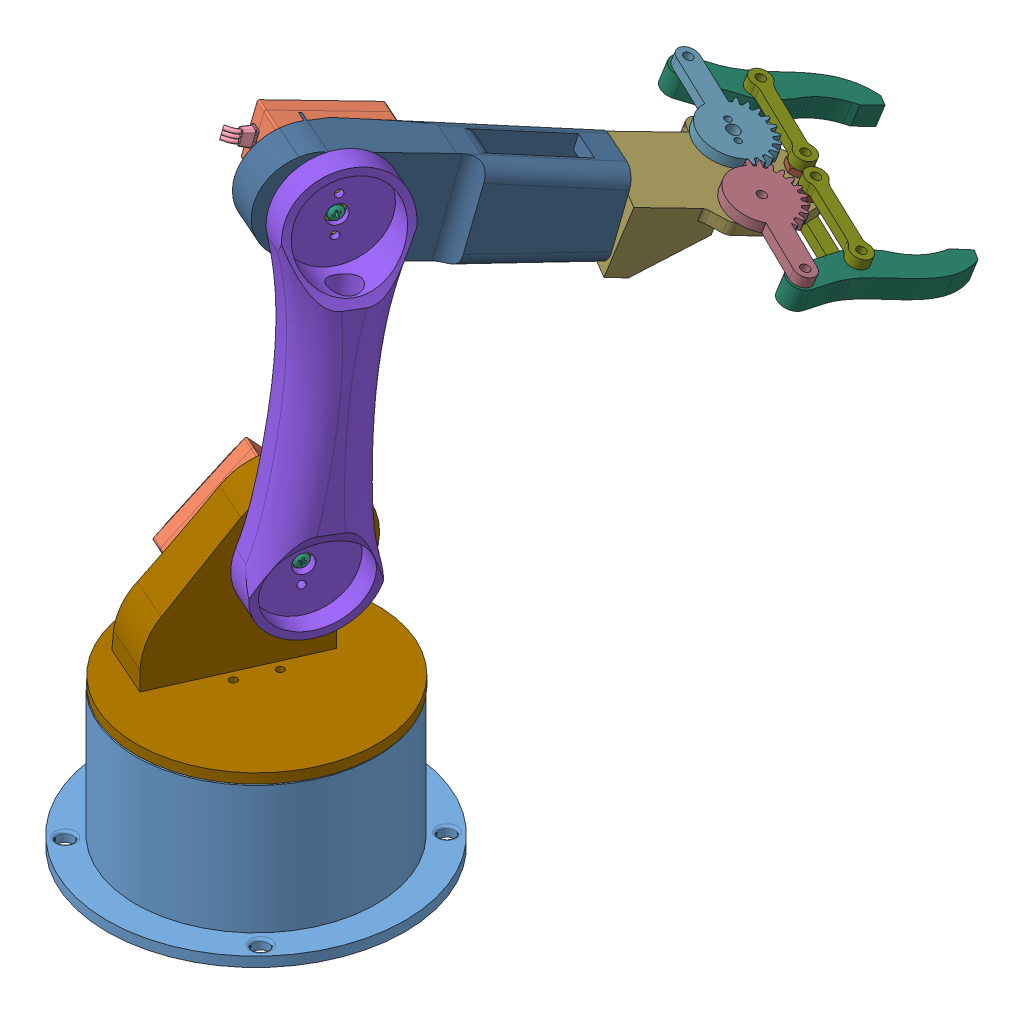
SolidWorks assembly Brazo Final, configuration Predeterminado. Lengths in mm.
Overall size (179.71 240.67 271.91).
47 component instances, 16 part files, 55 mates.
Components (placement in the parent):
- BaseFinal-1: BaseFinal [Predeterminado] at (-21.2055 -46.2716 0) size (121.25 56 121.25)
- MG996R Servo Motor-1: MG996R Servo Motor [Default] at (-10.8555 -16.9216 -0.4072) size (57.44 47.35 20)
  - Case-1: Case [Default] at origin size (54 39 20)
  - Output Shaft-1: Output Shaft [Default] at (-10.45 9.35 0) x (0.84541 0 0.534117) z (-0.534117 0 0.84541) size (13.78 15.2 13.78)
  - Rubber Wire Cable Sleeve-1: Rubber Wire Cable Sleeve [Default] at (-18.2 -12.025 0) size (15.24 5.03 7.75)
  - Pan Head Cross Screw M1.6-1: Pan Head Cross Screw M1.6 [Default] at (-17.575 12.35 7.125) x (0 1 0) z (0.509945 0 0.860207) size (32.17 3.2 3.2)
  - Pan Head Cross Screw M1.6-2: Pan Head Cross Screw M1.6 [Default] at (17.575 12.35 7.125) x (0 1 0) z (0.498431 0 0.86693) size (32.17 3.2 3.2)
  - Pan Head Cross Screw M1.6-3: Pan Head Cross Screw M1.6 [Default] at (17.575 12.35 -7.125) x (0 1 0) z (0.499198 0 0.866488) size (32.17 3.2 3.2)
  - Pan Head Cross Screw M1.6-4: Pan Head Cross Screw M1.6 [Default] at (-17.575 12.35 -7.125) x (0 1 0) z (0.500246 0 0.865884) size (32.17 3.2 3.2)
  - Pan Head Cross Screw M3-1: Pan Head Cross Screw M3 [Default] at (-10.45 20.85 0) x (0 -1 0) z (0.893136 0 -0.449786) size (8.51 5.6 5.6)
- Servo Horns-1: Servo Horns [Circular Horn] at (-21.3055 8.7784 -0.4072) x (-0.938379 0 -0.345608) z (-0.345608 0 0.938379) size (20 5.5 20)
- eslabon 1-1: eslabon 1 [Default] at (-18.1645 50.3106 -14.3588) x (0.404721 -0.090781 -0.909923) z (0.913696 0 0.406399) size (50.29 162 24.25)
- Base2-1: Base2 [Predeterminado] at (-21.3055 9.9284 -0.4072) x (0.913696 0 0.406399) z (-0.406399 0 0.913696) size (98 66.17 98)
- MG996R Servo Motor-2: MG996R Servo Motor [Default] at (-45.2434 42.9214 -18.3159) x (-0.287367 -0.707107 0.64608) z (-0.287367 0.707107 0.64608) size (57.44 47.35 20)
  - Case-1: Case [Default] at origin size (54 39 20)
  - Output Shaft-1: Output Shaft [Default] at (-10.45 9.35 0) x (0.84541 0 0.534117) z (-0.534117 0 0.84541) size (13.78 15.2 13.78)
  - Rubber Wire Cable Sleeve-1: Rubber Wire Cable Sleeve [Default] at (-18.2 -12.025 0) size (15.24 5.03 7.75)
  - Pan Head Cross Screw M1.6-1: Pan Head Cross Screw M1.6 [Default] at (-17.575 12.35 7.125) x (0 1 0) z (0.509945 0 0.860207) size (32.17 3.2 3.2)
  - Pan Head Cross Screw M1.6-2: Pan Head Cross Screw M1.6 [Default] at (17.575 12.35 7.125) x (0 1 0) z (0.498431 0 0.86693) size (32.17 3.2 3.2)
  - Pan Head Cross Screw M1.6-3: Pan Head Cross Screw M1.6 [Default] at (17.575 12.35 -7.125) x (0 1 0) z (0.499198 0 0.866488) size (32.17 3.2 3.2)
  - Pan Head Cross Screw M1.6-4: Pan Head Cross Screw M1.6 [Default] at (-17.575 12.35 -7.125) x (0 1 0) z (0.500246 0 0.865884) size (32.17 3.2 3.2)
  - Pan Head Cross Screw M3-1: Pan Head Cross Screw M3 [Default] at (-10.45 20.85 0) x (0 -1 0) z (0.893136 0 -0.449786) size (8.51 5.6 5.6)
- Servo Horns-2: Servo Horns [Circular Horn] at (-19.2152 50.3106 -14.8262) x (-0.21591 0.8472 0.485424) z (-0.344301 -0.531275 0.774083) size (20 5.5 20)
- ARM2-1: ARM2 [Predeterminado] at (-32.3016 176.3104 -6.1476) x (0.105578 0.965665 -0.237368) z (-0.913696 0 -0.406399) size (37.7 115 28.38)
- MG996R Servo Motor-3: MG996R Servo Motor [Default] at (-34.169 167.1004 -44.4444) x (0.392445 -0.259789 -0.882324) z (-0.105578 -0.965665 0.237368) size (57.44 47.35 20)
  - Case-1: Case [Default] at origin size (54 39 20)
  - Output Shaft-1: Output Shaft [Default] at (-10.45 9.35 0) x (0.84541 0 0.534117) z (-0.534117 0 0.84541) size (13.78 15.2 13.78)
  - Rubber Wire Cable Sleeve-1: Rubber Wire Cable Sleeve [Default] at (-18.2 -12.025 0) size (15.24 5.03 7.75)
  - Pan Head Cross Screw M1.6-1: Pan Head Cross Screw M1.6 [Default] at (-17.575 12.35 7.125) x (0 1 0) z (0.509945 0 0.860207) size (32.17 3.2 3.2)
  - Pan Head Cross Screw M1.6-2: Pan Head Cross Screw M1.6 [Default] at (17.575 12.35 7.125) x (0 1 0) z (0.498431 0 0.86693) size (32.17 3.2 3.2)
  - Pan Head Cross Screw M1.6-3: Pan Head Cross Screw M1.6 [Default] at (17.575 12.35 -7.125) x (0 1 0) z (0.499198 0 0.866488) size (32.17 3.2 3.2)
  - Pan Head Cross Screw M1.6-4: Pan Head Cross Screw M1.6 [Default] at (-17.575 12.35 -7.125) x (0 1 0) z (0.500246 0 0.865884) size (32.17 3.2 3.2)
  - Pan Head Cross Screw M3-1: Pan Head Cross Screw M3 [Default] at (-10.45 20.85 0) x (0 -1 0) z (0.893136 0 -0.449786) size (8.51 5.6 5.6)
- Servo Horns-5: Servo Horns [Circular Horn] at (-14.788 169.8151 -24.7797) x (0.369837 -0.414533 -0.831495) z (0.168466 0.910034 -0.378757) size (20 5.5 20)
- hex nut jam_am-1: hex nut jam_am [B18.2.4.5M - Hex jam nut,  M5 x 0.8 --D-N] at (47.5233 140.3234 -156.4542) x (0.800667 -0.145351 0.58121) z (-0.282922 -0.946869 0.152954) size (8 9.24 2.7)
- hex nut jam_am-2: hex nut jam_am [B18.2.4.5M - Hex jam nut,  M5 x 0.8 --D-N] at (47.4371 146.5591 -135.6639) x (-0.800817 0.145432 -0.580984) z (0.282922 0.946869 -0.152954) size (8 9.24 2.7)
- hex nut jam_am-3: hex nut jam_am [B18.2.4.5M - Hex jam nut,  M5 x 0.8 --D-N] at (38.7729 142.2186 -160.9082) x (0.535187 -0.02351 0.844407) z (-0.282922 -0.946869 0.152954) size (8 9.24 2.7)
- Gripper base-1: Gripper base [Predeterminado] at (28.487 136.213 -148.4635) x (-0.875181 0.189603 -0.445094) z (0.392445 -0.259789 -0.882324) size (44.4 28 63.3)
- gear1-1: gear1 [Predeterminado] at (47.4371 146.5591 -135.6639) x (0.915133 -0.218734 0.338656) z (-0.287206 0.235786 0.928395) size (49.27 4 26.61)
- hex nut jam_am-4: hex nut jam_am [B18.2.4.5M - Hex jam nut,  M5 x 0.8 --D-N] at (23.1313 149.1026 -147.2249) x (0.800791 -0.145418 0.581023) z (-0.282922 -0.946869 0.152954) size (8 9.24 2.7)
- gear2-2: gear2 [Predeterminado] at (23.8952 151.6591 -147.6378) x (0.876817 -0.190689 0.441395) z (-0.388776 0.258993 0.884181) size (49.03 4 26.64)
- Gripper link-1: Gripper link [Predeterminado] at (73.1621 131.7871 -123.954) x (-0.056496 0.175644 0.982831) z (0.282922 0.946869 -0.152954) size (65.35 20.4 8.5)
- grip link 1-3: grip link 1 [Predeterminado] at (62.5507 139.4245 -151.875) x (-0.919978 0.222792 -0.322497) z (0.271285 -0.231956 -0.934131) size (39 4 8.01)
- Gripper link-2: Gripper link [Predeterminado] at (-4.398 158.515 -157.5305) x (-0.703827 0.31329 0.637555) z (-0.282922 -0.946869 0.152954) size (65.35 20.4 8.5)
- grip link 1-4: grip link 1 [Predeterminado] at (25.3093 148.2 -166.4358) x (0.917648 -0.22082 0.330394) z (-0.279064 0.233834 0.931367) size (39 4 8.01)
- grip link 1-5: grip link 1 [Predeterminado] at (59.2405 128.3461 -150.0854) x (-0.919978 0.222792 -0.322497) z (0.271285 -0.231956 -0.934131) size (39 4 8.01)
- grip link 1-6: grip link 1 [Predeterminado] at (21.9991 137.1217 -164.6462) x (0.917648 -0.22082 0.330394) z (-0.279064 0.233834 0.931367) size (39 4 8.01)
Mates (geometry in assembly coordinates):
- Coincidente1: coincident anti-aligned: plane of BaseFinal-1 through (-21.2055 -8.2716 0) normal (0 1 0); plane of MG996R Servo Motor-1/Case-1 through (8.8945 -8.2716 8.8928) normal (0 -1 0)
- Distancia2: distance = 2.6 mm aligned: plane of BaseFinal-1 through (-40.4555 -8.2716 12.5928) normal (-1 0 0); plane of MG996R Servo Motor-1/Case-1 through (-37.8555 -5.7716 3.3928) normal (-1 0 0)
- Distancia3: distance = 3 mm aligned: plane of MG996R Servo Motor-1/Case-1 through (9.5945 -7.2716 9.5928) normal (0 0 1); plane of BaseFinal-1 through (-32.4555 -8.2716 12.5928) normal (0 0 1)
- Concéntrica1: concentric anti-aligned: circle of MG996R Servo Motor-1/Pan Head Cross Screw M3-1; circle of Servo Horns-1
- Coincidente10: coincident anti-aligned: plane of MG996R Servo Motor-1/Pan Head Cross Screw M3-1 through (-19.9658 9.9284 -1.0819) normal (0 -1 0); plane of Servo Horns-1 through (-21.3055 9.9284 -0.4072) normal (0 1 0)
- Concéntrica2: concentric anti-aligned: cylinder of MG996R Servo Motor-1/Pan Head Cross Screw M3-1 through (-21.3055 6.2805 -0.4072) axis (0 1 0) radius 2.8; cylinder of Base2-1 through (-21.3055 11.9284 -0.4072) axis (0 -1 0) radius 3.75
- Coincidente11: coincident anti-aligned: plane of Servo Horns-1 through (-21.3055 9.9284 -0.4072) normal (0 1 0); plane of Base2-1 through (-21.3055 9.9284 -0.4072) normal (0 -1 0)
- Coincidente13: coincident anti-aligned: plane of Base2-1 through (-26.9506 21.0364 -2.4792) normal (0.287367 0.707107 -0.64608); plane of MG996R Servo Motor-2/Case-1 through (-45.1765 35.5321 5.279) normal (-0.287367 -0.707107 0.64608)
- Distancia4: distance = 0.5 mm anti-aligned: plane of Base2-1 through (-15.1687 50.0274 -28.9682) normal (-0.287367 0.707107 0.64608); plane of MG996R Servo Motor-2/Case-1 through (-33.216 21.39 -4.8791) normal (0.287367 -0.707107 -0.64608)
- Coincidente15: coincident anti-aligned: plane of Base2-1 through (-28.8383 26.697 -27.7628) normal (-0.913696 0 -0.406399); plane of MG996R Servo Motor-2/Case-1 through (-29.883 66.2559 -25.414) normal (0.913696 0 0.406399)
- Coincidente16: coincident anti-aligned: plane of MG996R Servo Motor-2/Case-1 through (-23.1898 50.3106 -16.594) normal (0.913696 0 0.406399); plane of Servo Horns-2 through (-23.1898 50.3106 -16.594) normal (-0.913696 0 -0.406399)
- Concéntrica3: concentric anti-aligned: circle of MG996R Servo Motor-2/Pan Head Cross Screw M3-1; circle of Servo Horns-2
- Concéntrica4: concentric anti-aligned: circle of eslabon 1-1; circle of MG996R Servo Motor-2/Pan Head Cross Screw M3-1
- Coincidente19: coincident anti-aligned: plane of eslabon 1-1 through (-18.1645 50.3106 -14.3588) normal (-0.913696 0 -0.406399); plane of Servo Horns-2 through (-18.1645 50.3106 -14.3588) normal (0.913696 0 0.406399)
- Coincidente26: coincident anti-aligned: plane of ARM2-1 through (-23.0647 162.2736 -14.9068) normal (0.392445 -0.259789 -0.882324); plane of MG996R Servo Motor-3/Case-1 through (-26.1084 182.0697 -22.0893) normal (-0.392445 0.259789 0.882324)
- Distancia9: distance = 0.5 mm anti-aligned: plane of ARM2-1 through (-6.9744 151.6222 -51.0821) normal (0.105578 0.965665 -0.237368); plane of MG996R Servo Motor-3/Case-1 through (-28.22 162.7564 -17.3419) normal (-0.105578 -0.965665 0.237368)
- Coincidente33: coincident anti-aligned: plane of ARM2-1 through (-30.6608 171.5226 -24.8956) normal (-0.913696 0 -0.406399); plane of MG996R Servo Motor-3/Case-1 through (-34.7805 166.4825 -15.6335) normal (0.913696 0 0.406399)
- Concéntrica8: concentric aligned: circle of eslabon 1-1; circle of Servo Horns-5
- Coincidente36: coincident anti-aligned: plane of eslabon 1-1 through (-18.1645 50.3106 -14.3588) normal (-0.913696 0 -0.406399); plane of Servo Horns-5 through (-13.7373 169.8151 -24.3123) normal (0.913696 0 0.406399)
- Coincidente37: coincident anti-aligned: plane of MG996R Servo Motor-3/Pan Head Cross Screw M3-1 through (-13.1403 170.1186 -25.6545) normal (-0.913696 0 -0.406399); plane of Servo Horns-5 through (-13.7373 169.8151 -24.3123) normal (0.913696 0 0.406399)
- Concéntrica9: concentric anti-aligned: circle of MG996R Servo Motor-3/Pan Head Cross Screw M3-1; circle of Servo Horns-5
- Concéntrica10: concentric anti-aligned: circle of hex nut jam_am-3; circle of Gripper base-1
- Coincidente38: coincident anti-aligned: plane of hex nut jam_am-3 through (35.0965 143.7001 -158.5369) normal (-0.282922 -0.946869 0.152954); plane of Gripper base-1 through (31.4577 146.1552 -150.0696) normal (0.282922 0.946869 -0.152954)
- Concéntrica11: concentric anti-aligned: circle of hex nut jam_am-1; circle of Gripper base-1
- Coincidente39: coincident anti-aligned: plane of hex nut jam_am-1 through (45.0841 141.6486 -152.7626) normal (-0.282922 -0.946869 0.152954); plane of Gripper base-1 through (31.4577 146.1552 -150.0696) normal (0.282922 0.946869 -0.152954)
- Concéntrica12: concentric aligned: circle of hex nut jam_am-2; circle of Gripper base-1
- Coincidente40: coincident anti-aligned: plane of hex nut jam_am-2 through (44.2351 145.3275 -131.5586) normal (-0.282922 -0.946869 0.152954); plane of Gripper base-1 through (31.4577 146.1552 -150.0696) normal (0.282922 0.946869 -0.152954)
- Concéntrica13: concentric aligned: circle of hex nut jam_am-2; circle of gear1-1
- Coincidente41: coincident anti-aligned: plane of hex nut jam_am-2 through (44.999 147.884 -131.9716) normal (0.282922 0.946869 -0.152954); plane of gear1-1 through (47.4371 146.5591 -135.6639) normal (-0.282922 -0.946869 0.152954)
- Concéntrica16: concentric anti-aligned: circle of ARM2-1; circle of Gripper base-1
- Coincidente42: coincident anti-aligned: plane of ARM2-1 through (12.8296 146.4346 -107.6149) normal (0.392445 -0.259789 -0.882324); plane of Gripper base-1 through (30.8559 154.1225 -101.8607) normal (-0.392445 0.259789 0.882324)
- Concéntrica18: concentric aligned: circle of Gripper base-1; circle of hex nut jam_am-4
- Coincidente44: coincident anti-aligned: plane of Gripper base-1 through (31.4577 146.1552 -150.0696) normal (0.282922 0.946869 -0.152954); plane of hex nut jam_am-4 through (20.693 150.4276 -143.5327) normal (-0.282922 -0.946869 0.152954)
- Concéntrica19: concentric anti-aligned: circle of hex nut jam_am-4; circle of gear2-2
- Coincidente45: coincident anti-aligned: plane of hex nut jam_am-4 through (21.4568 152.9841 -143.9456) normal (0.282922 0.946869 -0.152954); plane of gear2-2 through (23.8952 151.6591 -147.6378) normal (-0.282922 -0.946869 0.152954)
- Relación de posición de engranaje1: gear = 24.16 : 24.169 mm: cylinder of gear2-2 through (25.0269 155.4466 -148.2496) axis (-0.282922 -0.946869 0.152954) radius 12.0845; cylinder of gear1-1 through (48.5688 150.3465 -136.2757) axis (-0.282922 -0.946869 0.152954) radius 12.08
- Concéntrica21: concentric aligned: circle of gear1-1; circle of Gripper link-1
- Coincidente47: coincident anti-aligned: plane of gear1-1 through (47.4371 146.5591 -135.6639) normal (-0.282922 -0.946869 0.152954); plane of Gripper link-1 through (75.567 139.8355 -125.2541) normal (0.282922 0.946869 -0.152954)
- Concéntrica22: concentric aligned: circle of Gripper link-1; circle of grip link 1-3
- Coincidente48: coincident anti-aligned: plane of Gripper link-1 through (75.567 139.8355 -125.2541) normal (0.282922 0.946869 -0.152954); plane of grip link 1-3 through (52.1383 141.4874 -158.3647) normal (-0.282922 -0.946869 0.152954)
- Concéntrica23: concentric anti-aligned: circle of hex nut jam_am-1; circle of grip link 1-3
- Coincidente49: coincident anti-aligned: plane of hex nut jam_am-1 through (45.848 144.2051 -153.1756) normal (0.282922 0.946869 -0.152954); plane of grip link 1-3 through (52.1383 141.4874 -158.3647) normal (-0.282922 -0.946869 0.152954)
- Concéntrica24: concentric anti-aligned: circle of gear2-2; circle of Gripper link-2
- Coincidente50: coincident anti-aligned: plane of gear2-2 through (23.8952 151.6591 -147.6378) normal (-0.282922 -0.946869 0.152954); plane of Gripper link-2 through (-4.398 158.515 -157.5305) normal (0.282922 0.946869 -0.152954)
- Concéntrica25: concentric anti-aligned: circle of hex nut jam_am-3; circle of grip link 1-4
- Coincidente51: coincident anti-aligned: plane of hex nut jam_am-3 through (35.8604 146.2566 -158.9499) normal (0.282922 0.946869 -0.152954); plane of grip link 1-4 through (35.6719 146.1663 -159.8579) normal (-0.282922 -0.946869 0.152954)
- Concéntrica26: concentric anti-aligned: circle of Gripper link-2; circle of grip link 1-4
- Coincidente52: coincident anti-aligned: plane of Gripper link-1 through (75.567 139.8355 -125.2541) normal (0.282922 0.946869 -0.152954); plane of grip link 1-3 through (52.1383 141.4874 -158.3647) normal (-0.282922 -0.946869 0.152954)
- Coincidente53: coincident anti-aligned: plane of Gripper link-2 through (-4.398 158.515 -157.5305) normal (0.282922 0.946869 -0.152954); plane of grip link 1-4 through (35.6719 146.1663 -159.8579) normal (-0.282922 -0.946869 0.152954)
- Coincidente54: coincident anti-aligned: circle of Gripper base-1; circle of grip link 1-6
- Coincidente55: coincident anti-aligned: plane of Gripper base-1 through (8.3376 148.8097 -143.7128) normal (-0.282922 -0.946869 0.152954); plane of grip link 1-6 through (33.4934 138.8754 -158.6801) normal (0.282922 0.946869 -0.152954)
- Concéntrica27: concentric anti-aligned: circle of Gripper link-2; circle of grip link 1-6
- Coincidente56: coincident anti-aligned: circle of Gripper base-1; circle of grip link 1-5
- Concéntrica28: concentric aligned: circle of Gripper link-1; circle of grip link 1-5
- Paralelo1: parallel anti-aligned: plane of Gripper link-1 through (73.1621 131.7871 -123.954) normal (-0.282922 -0.946869 0.152954); plane of grip link 1-5 through (49.9598 134.1965 -157.187) normal (0.282922 0.946869 -0.152954)
